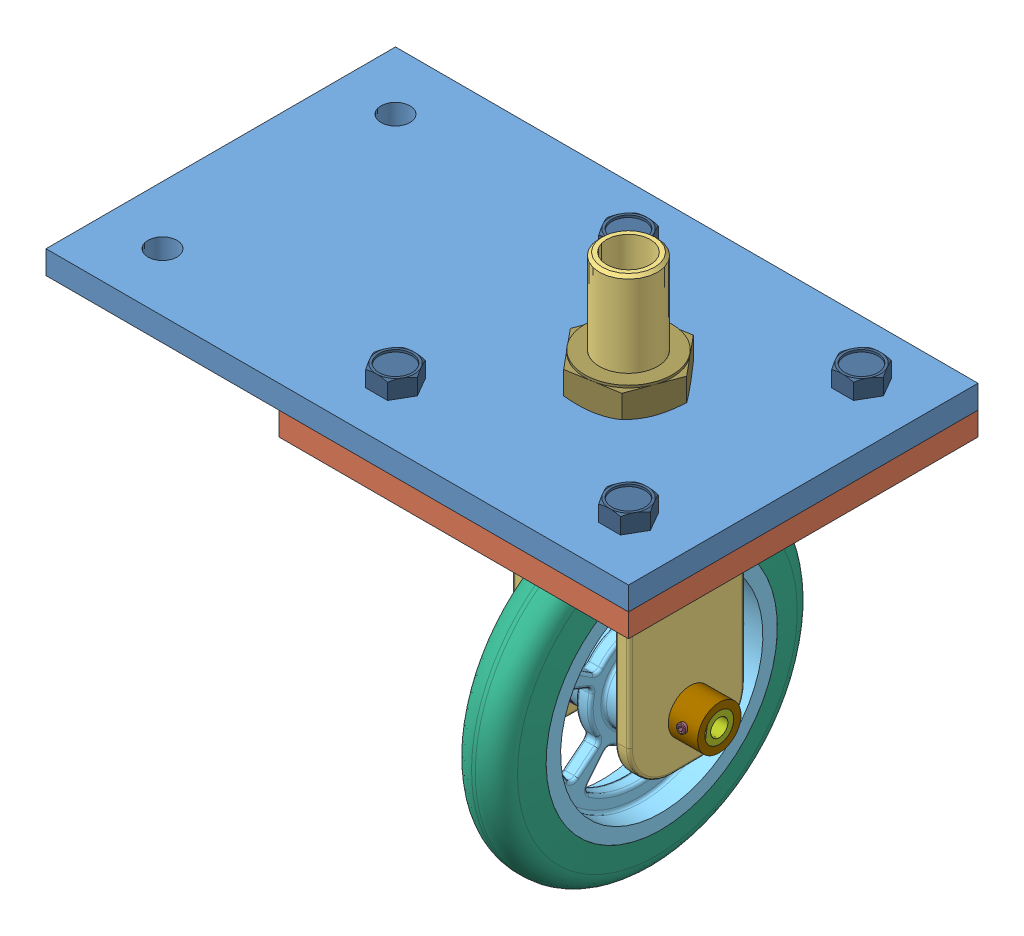
SolidWorks assembly Caster, configuration Default. Lengths in mm.
Overall size (200 190.28 127.02).
23 component instances, 13 part files, 19 mates.
Components (placement in the parent):
- Base-3: Base [Default] at (121.3735 -78.9245 111.3642) size (200 8 120)
- Mount-2: Mount [Default] at (171.0143 -86.9245 131.4776) size (120 8 120)
- Fork-1: Fork [Default] at (171.0143 -99.9245 131.4776) x (-0.007678 0 -0.999971) z (0.999971 0 -0.007678) size (80 143 80)
- Bearing-2: Bearing [Default] at (171.0143 -86.9245 131.4776) x (-0.132169 0 0.991227) z (0 -1 0) size (30 30 5)
- Wheel and Axle-1: Wheel and Axle [Default] at (214.5171 -124.7496 70.7676) x (-0.999971 0 0.007678) z (0.007574 0.16412 0.986411) size (60 110 110)
  - Wheel-1: Wheel [Default] at (43.5901 43.4624 52.9982) size (20 80 80)
  - Tire-1: Tire [Default] at (43.5901 43.4624 52.9982) x (0 0 -1) z (0 1 0) size (110 20 110)
  - Axle-2: Axle [Default] at (43.9894 43.4624 52.9982) x (0 1 0) z (-1 0 0) size (10 10 60)
  - Washer-2: Washer [Default] at (31.0901 43.4624 52.9982) size (5 25 25)
  - Washer-3: Washer [Default] at (56.4676 43.4624 52.9982) size (5 25 25)
- Collar-2: Collar [Default] at (196.0062 -158.9245 130.3241) x (-0.00126 0.98644 -0.164115) z (-0.007574 -0.16412 -0.986411) size (15 10 15)
- Collar-5: Collar [Default] at (146.0077 -158.9245 130.708) x (0.00126 -0.98644 0.164115) z (-0.007574 -0.16412 -0.986411) size (15 10 15)
- hex screw_am-8: hex screw_am [B18.6.7M - M8 x 1.25 x 25 Indented HHMS --25N] at (131.0143 -64.9245 171.4776) x (0 -1 0) z (0 0 1) size (31 15.01 13)
- hex nut style 1_am-4: hex nut style 1_am [B18.2.4.1M - Hex nut, Style 1,  M8 x 1.25 --D-N] at (131.0143 -86.9422 171.4776) x (-0.721884 0 0.692014) z (0 1 0) size (13 15.01 6.8)
- hex nut style 1_am-5: hex nut style 1_am [B18.2.4.1M - Hex nut, Style 1,  M8 x 1.25 --D-N] at (211.0143 -86.9422 91.4776) x (-0.721884 0 0.692014) z (0 1 0) size (13 15.01 6.8)
- hex nut style 1_am-6: hex nut style 1_am [B18.2.4.1M - Hex nut, Style 1,  M8 x 1.25 --D-N] at (131.0143 -86.9422 91.4776) x (-0.721884 0 0.692014) z (0 1 0) size (13 15.01 6.8)
- hex nut style 1_am-7: hex nut style 1_am [B18.2.4.1M - Hex nut, Style 1,  M8 x 1.25 --D-N] at (211.0143 -86.9422 171.4776) x (-0.721884 0 0.692014) z (0 1 0) size (13 15.01 6.8)
- hex screw_am-9: hex screw_am [B18.6.7M - M8 x 1.25 x 25 Indented HHMS --25N] at (211.0143 -64.9245 91.4776) x (0 -1 0) z (0 0 1) size (31 15.01 13)
- hex screw_am-10: hex screw_am [B18.6.7M - M8 x 1.25 x 25 Indented HHMS --25N] at (131.0143 -64.9245 91.4776) x (0 -1 0) z (0 0 1) size (31 15.01 13)
- hex screw_am-11: hex screw_am [B18.6.7M - M8 x 1.25 x 25 Indented HHMS --25N] at (211.0143 -64.9245 171.4776) x (0 -1 0) z (0 0 1) size (31 15.01 13)
- hex nut jam_am-1: hex nut jam_am [B18.2.4.5M - Hex jam nut,  M20 x 2.5 --W-N] at (171.0143 -70.9245 131.4776) x (0.769991 0 -0.638055) z (0 -1 0) size (30 34.64 10)
- socket set screw flat point_am-1: socket set screw flat point_am [B18.3.6M - M3 x 0.5 x 4 Hex Socket Flat Pt. SS --N] at (196.0706 -157.5295 138.7086) x (-0.007574 -0.16412 -0.986411) z (0.120356 0.979119 -0.163831) size (4 3 3)
- socket set screw flat point_am-2: socket set screw flat point_am [B18.3.6M - M3 x 0.5 x 4 Hex Socket Flat Pt. SS --N] at (146.072 -157.5295 139.0925) x (-0.007574 -0.16412 -0.986411) z (0.687211 0.715734 -0.124361) size (4 3 3)
Mates (geometry in assembly coordinates):
- Coincident18: coincident anti-aligned: circle of Base-3; circle of Mount-2
- Coincident19: coincident anti-aligned: plane of Fork-1 through (171.0143 -91.9245 131.4776) normal (0 1 0); circle of Bearing-2
- Concentric7: concentric aligned: circle of Mount-2; circle of Bearing-2
- Coincident20: coincident anti-aligned: circle of Fork-1; circle of Wheel and Axle-1/Washer-3
- Parallel4: parallel anti-aligned: plane of Wheel and Axle-1/Axle-2 through (191.0214 -160.3359 135.1592) normal (0.007574 0.16412 0.986411); plane of Collar-2 through (196.0062 -158.9245 130.3241) normal (-0.007574 -0.16412 -0.986411)
- Coincident22: coincident anti-aligned: circle of Fork-1; circle of Collar-2
- Coincident45: coincident aligned: circle of Fork-1; circle of Collar-5
- Concentric11: concentric aligned: cylinder of Base-3 through (131.0143 -78.9245 171.4776) axis (0 1 0) radius 5; cylinder of hex screw_am-8 through (131.0143 -39.5245 171.4776) axis (0 1 0) radius 4
- Coincident46: coincident anti-aligned: plane of Base-3 through (121.3735 -70.9245 111.3642) normal (0 1 0); plane of hex screw_am-8 through (135.0143 -70.9245 171.4776) normal (0 -1 0)
- Concentric19: concentric aligned: cylinder of hex screw_am-8 through (131.0143 -39.5245 171.4776) axis (0 1 0) radius 4; cylinder of hex nut style 1_am-4 through (131.0143 -111.9797 171.4776) axis (0 1 0) radius 4
- Concentric20: concentric anti-aligned: circle of Mount-2; circle of hex nut style 1_am-4
- Concentric21: concentric aligned: cylinder of Fork-1 through (171.0143 -31.9245 131.4776) axis (0 -1 0) radius 10; cylinder of hex nut jam_am-1 through (171.0143 -45.887 131.4776) axis (0 -1 0) radius 10
- Coincident51: coincident anti-aligned: plane of Base-3 through (121.3735 -70.9245 111.3642) normal (0 1 0); plane of hex nut jam_am-1 through (182.0657 -70.9245 144.8142) normal (0 -1 0)
- Concentric25: concentric anti-aligned: cylinder of Collar-5 through (146.0645 -157.6935 138.107) axis (-0.007574 -0.16412 -0.986411) radius 1.5; cylinder of socket set screw flat point_am-2 through (146.1682 -155.4452 151.6199) axis (0.007574 0.16412 0.986411) radius 1.5
- Coincident54: coincident anti-aligned: plane of Wheel and Axle-1/Axle-2 through (151.0225 -160.3359 135.4663) normal (0.007574 0.16412 0.986411); plane of socket set screw flat point_am-2 through (145.3153 -157.5072 135.0395) normal (-0.007574 -0.16412 -0.986411)
- Coincident56: coincident anti-aligned: plane of Mount-2 through (171.0143 -86.9245 131.4776) normal (0 -1 0); plane of Bearing-2 through (171.0143 -86.9245 131.4776) normal (0 1 0)
- Concentric26: concentric aligned: cylinder of Base-3 through (171.0143 -28.9245 131.4776) axis (0 -1 0) radius 12.5; cylinder of Fork-1 through (171.0143 -31.9245 131.4776) axis (0 -1 0) radius 10
- Concentric28: concentric anti-aligned: cylinder of Collar-2 through (196.063 -157.6935 137.7232) axis (-0.007574 -0.16412 -0.986411) radius 1.5; cylinder of socket set screw flat point_am-1 through (196.1668 -155.4452 151.236) axis (0.007574 0.16412 0.986411) radius 1.5
- Coincident60: coincident anti-aligned: plane of Wheel and Axle-1/Axle-2 through (191.0214 -160.3359 135.1592) normal (0.007574 0.16412 0.986411); plane of socket set screw flat point_am-1 through (195.0476 -158.066 134.7506) normal (-0.007574 -0.16412 -0.986411)
